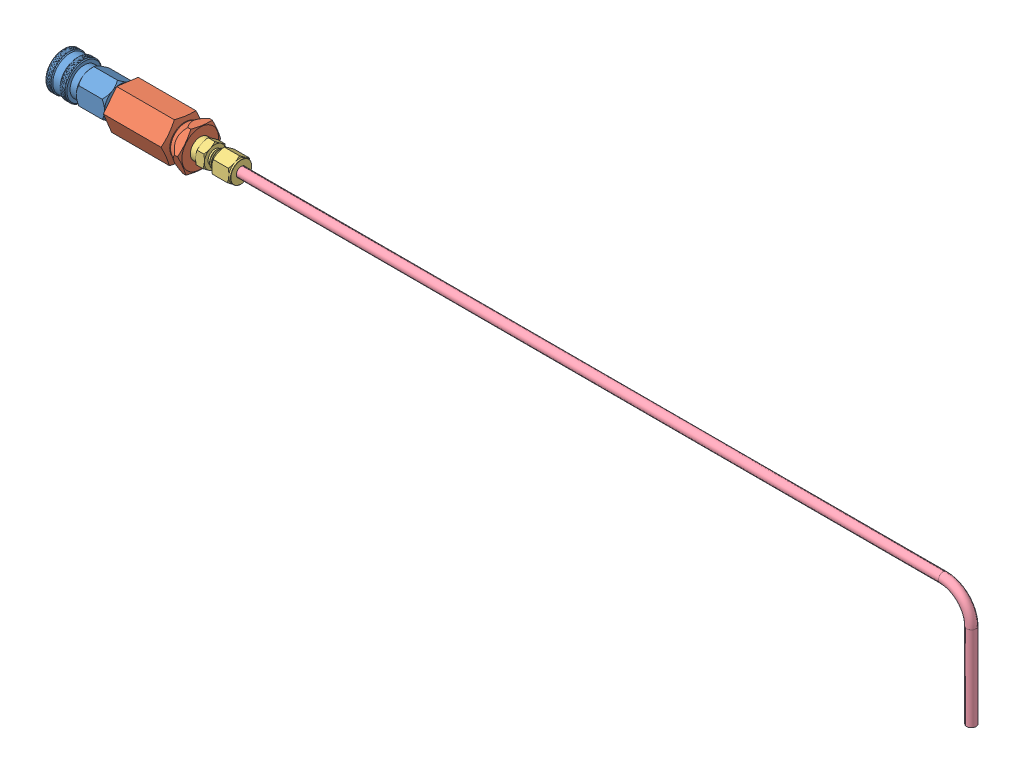
SolidWorks assembly Rocket QD, configuration Default. Lengths in mm.
Overall size (615.99 95.36 35.3).
4 component instances, 4 part files, 6 mates.
Components (placement in the parent):
- QDF -4FNPT-1: QDF -4FNPT [6543K33] at (24.797 22.4876 31.9473) size (38.1 26.13 24.65)
- HP Check Valve-1: HP Check Valve [6543K43] at (15.907 22.4876 31.9473) x (-1 0 0) z (0 -0.924225 -0.381849) size (63.16 25.4 30.98)
- -4S -4MNPT-1: -4S -4MNPT [5182K111] at (106.7556 22.4876 31.9473) x (0 -0.902106 -0.431514) z (1 0 0) size (14.29 16.5 37.85)
- -4 Al6061 Bend90 R.75 HighPress-1: -4 Al6061 Bend90 R.75 HighPress [Default] at (581.988 22.4876 31.9473) x (0 -1 0) z (0 0 1) size (79.38 511.17 6.35)
Mates (geometry in assembly coordinates):
- Distance1: distance = 10.16 mm anti-aligned: plane of HP Check Valve-1 through (15.907 22.4876 31.9473) normal (-1 0 0); plane of QDF -4FNPT-1 through (5.747 22.4876 31.9473) normal (1 0 0)
- Concentric2: concentric anti-aligned: cylinder of QDF -4FNPT-1 through (24.797 22.4876 31.9473) axis (-1 0 0) radius 4.5244; cylinder of HP Check Valve-1 through (-7.969 22.4876 31.9473) axis (1 0 0) radius 3.0956
- Concentric3: concentric aligned: cylinder of HP Check Valve-1 through (-7.969 22.4876 31.9473) axis (1 0 0) radius 3.0956; cylinder of -4S -4MNPT-1 through (106.7556 22.4876 31.9473) axis (1 0 0) radius 4.6228
- Distance2: distance = 10.16 mm anti-aligned: plane of HP Check Valve-1 through (79.0696 22.4876 31.9473) normal (1 0 0); plane of -4S -4MNPT-1 through (68.9096 22.4876 31.9473) normal (-1 0 0)
- Coincident2: coincident anti-aligned: plane of -4S -4MNPT-1 through (91.5156 23.8576 29.0831) normal (1 0 0); plane of -4 Bend30 HP Fill-1 through (91.5156 22.4876 31.9473) normal (-1 0 0)
- Concentric4: concentric aligned: cylinder of -4S -4MNPT-1 through (106.7556 22.4876 31.9473) axis (1 0 0) radius 2.3749; cylinder of -4 Bend30 HP Fill-1 through (91.5156 22.4876 31.9473) axis (1 0 0) radius 1.524
